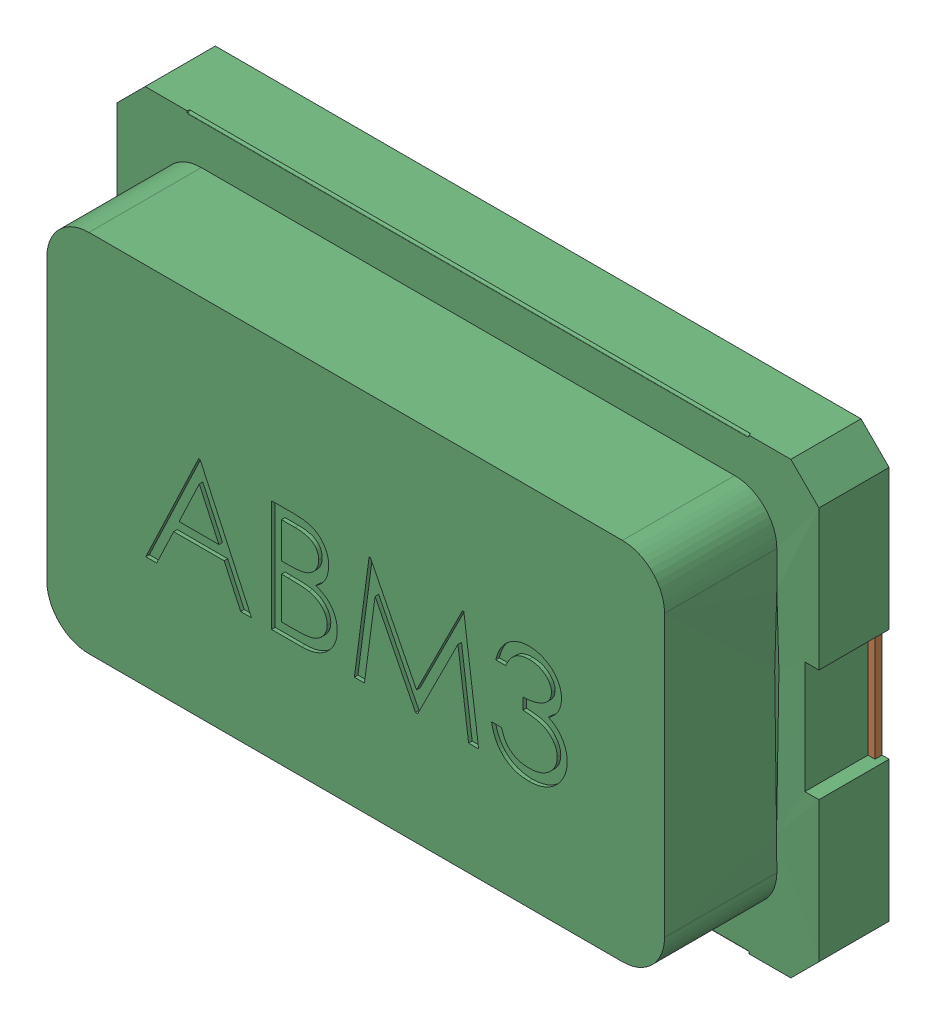
SolidWorks assembly Open CASCADE STEP translator 6.8 1.4.1, configuration Predeterminado. Lengths in mm.
Overall size (5 3.22 1.3).
4 component instances, 3 part files, 0 mates.
Components (placement in the parent):
- Body_1_2-1: Body_1_2 [Predeterminado] at (0 0 0.25) x (1 0 0) z (0 -1 0) size (5 1.3 3.22)
  - =_[0_1_1_3]-1: =_[0_1_1_3] [Predeterminado] at origin size (1.25 0.05 2)
  - =_[0_1_1_4]-1: =_[0_1_1_4] [Predeterminado] at origin size (1.25 0.05 2)
  - =_[0_1_1_5]-1: =_[0_1_1_5] [Predeterminado] at origin size (5 1.3 3.22)
